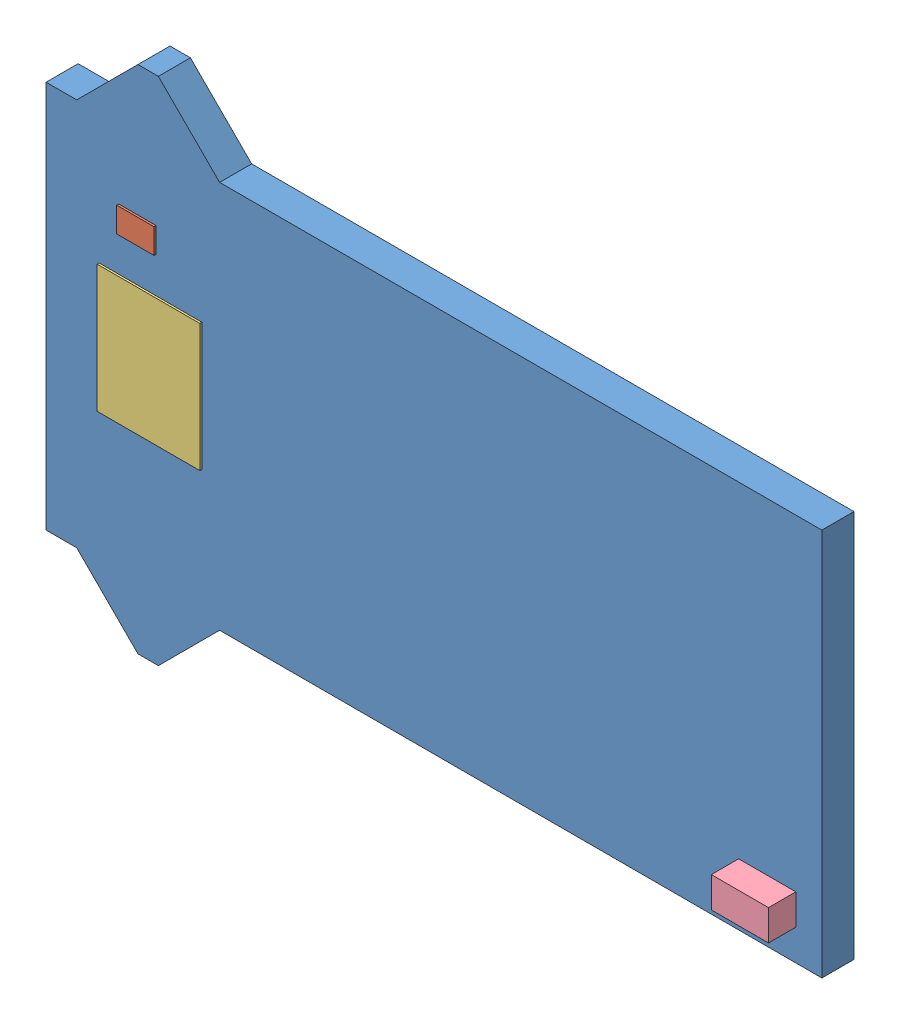
SolidWorks assembly EncoderV2-final, configuration Default. Lengths in mm.
Overall size (38 25 2.91).
6 component instances, 4 part files, 0 mates.
Components (placement in the parent):
- EncoderV2-final.step-1: EncoderV2-final.step [Default] at origin size (38 25 2.91)
  - PCB Component.step-1: PCB Component.step [Default] at origin size (38 25 2.91)
    - Board.step-1: Board.step [Default] at origin size (38 25 1.57)
    - 100nf.step-1: 100nf.step [Default] at (4.475 15.003 1.57) x (-1 0 0) z (0 0 1) size (1.83 1.22 0.1)
    - TSSOP14.step-1: TSSOP14.step [Default] at (5.116 9.511 1.57) size (5.03 6.24 0.1)
    - 06FLZ-SM1.step-1: 06FLZ-SM1.step [Default] at (35.324 -0.233 1.57) size (2.8 1.5 1.34)
